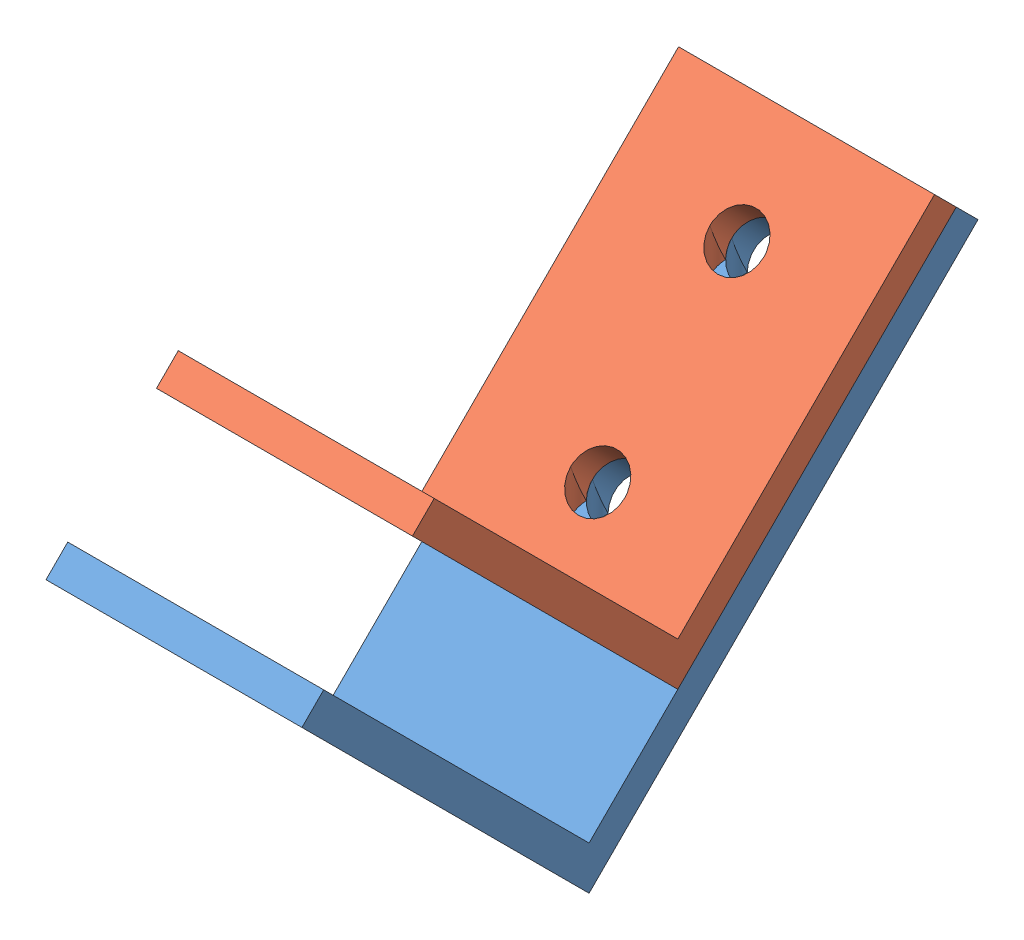
SolidWorks assembly Assem1, configuration Default. Lengths in mm.
Overall size (13.21 22.32 34.89).
2 component instances, 2 part files, 3 mates.
Components (placement in the parent):
- eyeBracketHalf2-1: eyeBracketHalf2 [Default] at (-3.6762 -9.1776 8.175) size (13.21 21.19 34.89)
- eyeBracketHalf1-1: eyeBracketHalf1 [Default] at (-3.6762 -2.3526 3.5951) size (13.21 15.49 28.06)
Mates (geometry in assembly coordinates):
- Concentric1: concentric aligned: cylinder of eyeBracketHalf2-1 through (2.9278 25.3066 9.7017) axis (0 -0.707107 -0.707107) radius 1.397; cylinder of eyeBracketHalf1-1 through (2.9278 23.0166 7.4117) axis (0 -0.707107 -0.707107) radius 1.397
- Concentric2: concentric aligned: cylinder of eyeBracketHalf2-1 through (2.9278 18.1224 16.8859) axis (0 -0.707107 -0.707107) radius 1.397; cylinder of eyeBracketHalf1-1 through (2.9278 15.8324 14.5959) axis (0 -0.707107 -0.707107) radius 1.397
- Coincident1: coincident anti-aligned: plane of eyeBracketHalf2-1 through (9.5318 -6.9326 8.175) normal (0 0.707107 0.707107); plane of eyeBracketHalf1-1 through (9.5318 12.0158 -10.7733) normal (0 -0.707107 -0.707107)
